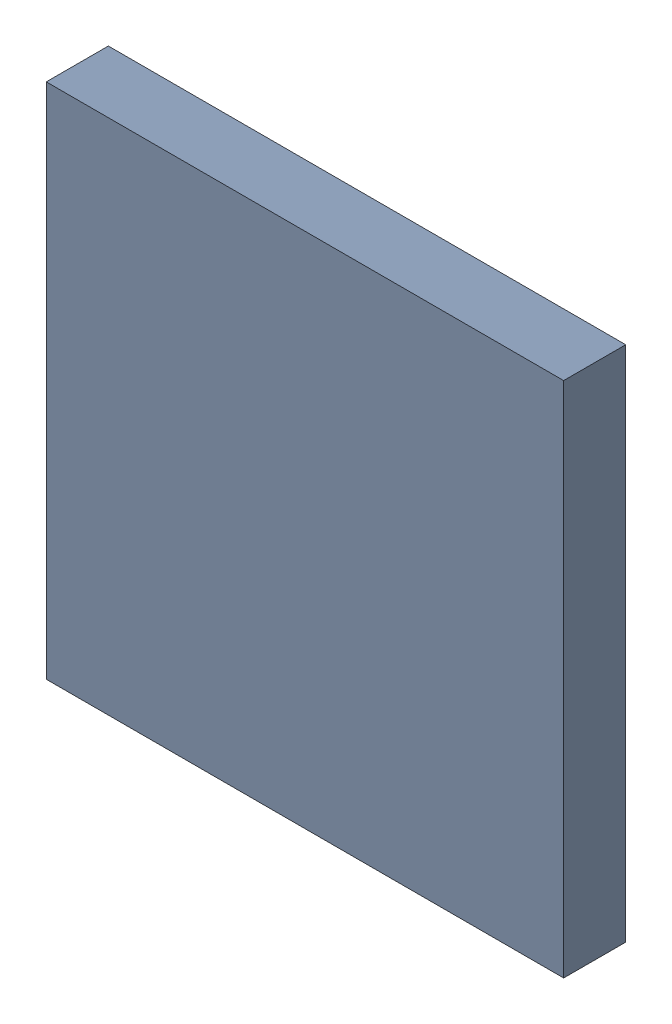
SolidWorks assembly ATmega32U4, configuration Default. Lengths in mm.
Overall size (10 10 1.2).
2 component instances, 1 part files, 0 mates.
Components (placement in the parent):
- 7433191200-1: 7433191200 [Default] at (148.8 79.4 -2.8914) size (10 10 1.2)
  - Extruded_5-1: Extruded_5 [Default] at origin size (10 10 1.2)
